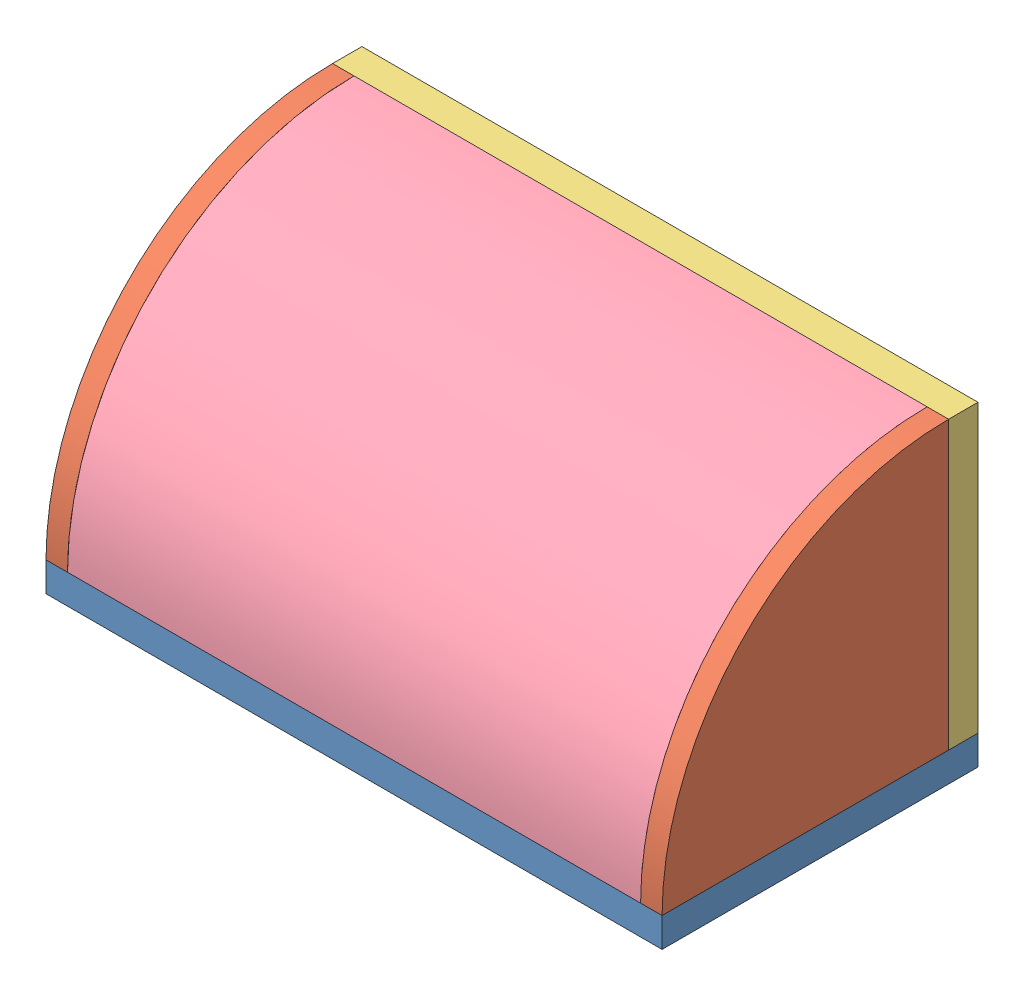
SolidWorks assembly omhulsel auto logo, configuration Default. Lengths in mm.
Overall size (86 44.1 44.1).
5 component instances, 4 part files, 12 mates.
Components (placement in the parent):
- logo hotwheels onderstuk-1: logo hotwheels onderstuk [Default] at (39.9465 43.5906 63.8014) size (86 4.3 44.1)
- ronde zijkant-1: ronde zijkant [Default] at (79.9465 43.5906 85.8514) size (3 40 40)
- ronde zijkant-2: ronde zijkant [Default] at (-3.0535 43.5906 85.8514) size (3 40 40)
- logo hotwheels zijkant-1: logo hotwheels zijkant [Default] at (39.9465 63.5906 45.8514) x (1 0 0) z (0 -1 0) size (86 4.3 40)
- zijkant krom-1: zijkant krom [Default] at (39.9465 43.5904 45.8512) size (80 40 40)
Mates (geometry in assembly coordinates):
- Coincident2: coincident: plane of logo hotwheels onderstuk-1 through (39.9465 43.5906 63.8014) normal (0 1 0); plane of ronde zijkant-1 through (82.9465 43.5906 85.8514) normal (0 -1 0)
- Coincident3: coincident: plane of logo hotwheels onderstuk-1 through (82.9465 39.4906 85.8514) normal (1 0 0); plane of ronde zijkant-1 through (82.9465 43.5906 45.8514) normal (1 0 0)
- Coincident4: coincident: plane of logo hotwheels onderstuk-1 through (82.9465 39.4906 85.8514) normal (0 0 1); line of ronde zijkant-1 through (82.9465 43.5906 85.8514) axis (-1 0 0)
- Coincident10: coincident: plane of logo hotwheels onderstuk-1 through (-3.0535 39.4906 85.8514) normal (-1 0 0); plane of ronde zijkant-2 through (-3.0535 43.5906 45.8514) normal (-1 0 0)
- Coincident11: coincident: plane of logo hotwheels onderstuk-1 through (39.9465 43.5906 63.8014) normal (0 1 0); plane of ronde zijkant-2 through (-0.0535 43.5906 85.8514) normal (0 -1 0)
- Coincident12: coincident: plane of logo hotwheels onderstuk-1 through (82.9465 39.4906 85.8514) normal (0 0 1); line of ronde zijkant-2 through (-0.0535 43.5906 85.8514) axis (-1 0 0)
- Coincident16: coincident: plane of logo hotwheels onderstuk-1 through (-3.0535 39.4906 85.8514) normal (-1 0 0); plane of logo hotwheels zijkant-1 through (-3.0535 43.5906 41.7514) normal (-1 0 0)
- Coincident17: coincident: plane of logo hotwheels onderstuk-1 through (39.9465 43.5906 63.8014) normal (0 1 0); plane of logo hotwheels zijkant-1 through (82.9465 43.5906 41.7514) normal (0 -1 0)
- Coincident18: coincident: plane of ronde zijkant-2 through (-0.0535 43.5906 45.8514) normal (0 0 -1); plane of logo hotwheels zijkant-1 through (39.9465 63.5906 45.8514) normal (0 0 1)
- Coincident19: coincident: plane of ronde zijkant-2 through (-0.0535 43.5906 45.8514) normal (1 0 0); plane of zijkant krom-1 through (-0.0535 43.5906 45.8514) normal (-1 0 0)
- Coincident20: coincident: plane of logo hotwheels zijkant-1 through (39.9465 63.5906 45.8514) normal (0 0 1); plane of zijkant krom-1 through (79.9465 80.5906 45.8514) normal (0 0 -1)
- Coincident21: coincident: plane of logo hotwheels onderstuk-1 through (39.9465 43.5906 63.8014) normal (0 1 0); plane of zijkant krom-1 through (79.9465 43.5906 82.8514) normal (0 -1 0)
